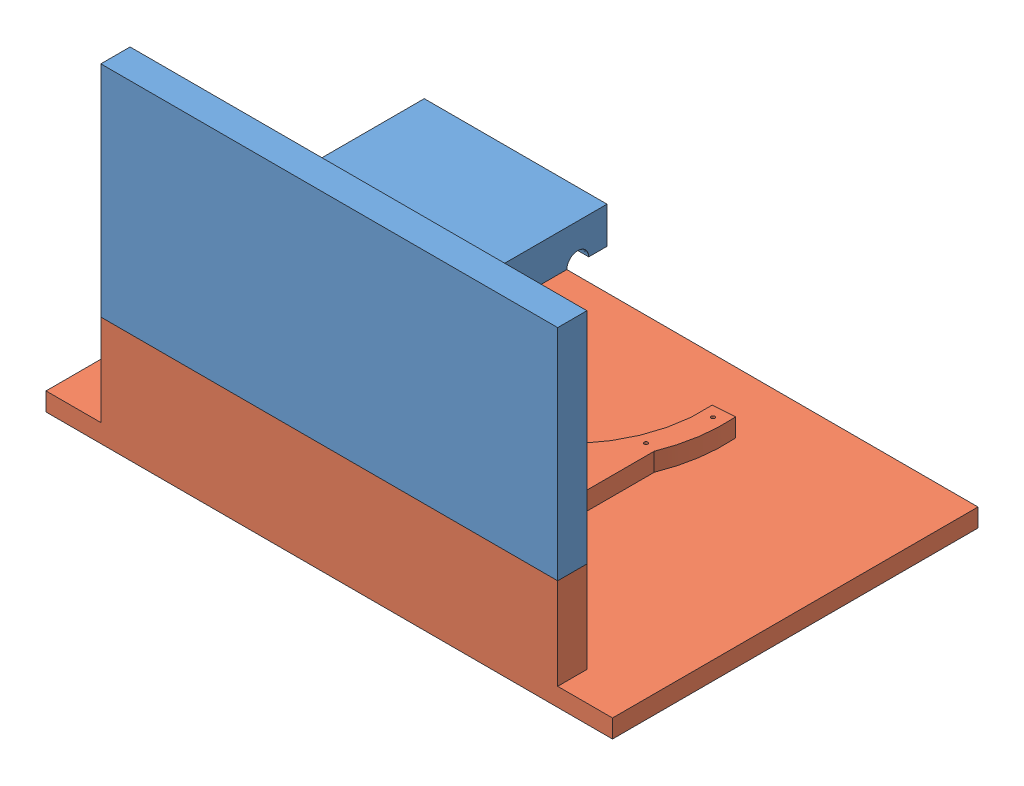
SolidWorks assembly setup, configuration 默认. Lengths in mm.
Overall size (155 90 100).
2 component instances, 2 part files, 2 mates.
Components (placement in the parent):
- 夹具-1: 夹具 [默认] at (-203.7117 -8.5743 150.5) size (125 75 51)
- ctrl_c_穿透-1: ctrl_c_穿透 [默认] at (-218.7117 -38.5743 150.5) size (155 30 100)
Mates (geometry in assembly coordinates):
- 重合7: coincident aligned: line of 夹具-1 through (-203.7117 -8.5743 142.5) axis (0 0 1); line of ctrl_c_穿透-1 through (-203.7117 -8.5743 142.5) axis (0 0 1)
- 重合8: coincident aligned: plane of 夹具-1 through (-203.7117 51.4257 150.5) normal (0 0 1); plane of ctrl_c_穿透-1 through (-218.7117 -33.5743 150.5) normal (0 0 1)
